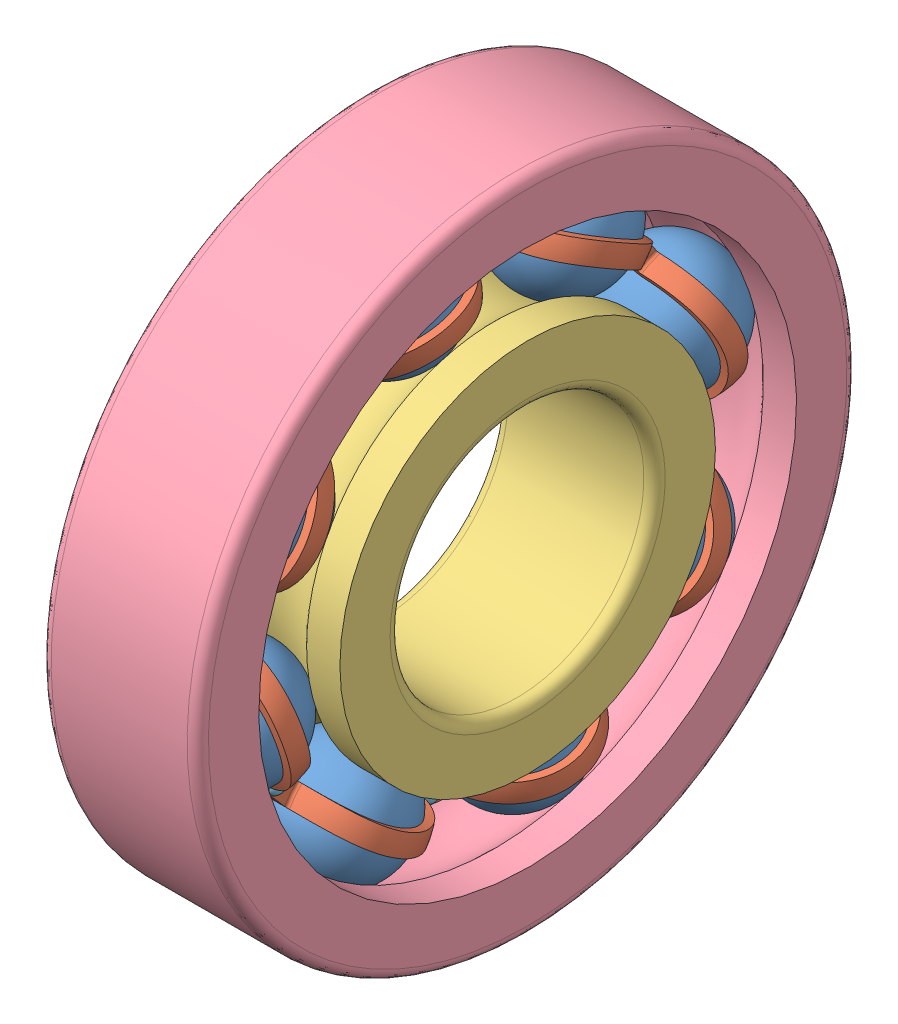
SolidWorks assembly ball_bearing, configuration Default. Lengths in mm.
Overall size (3.72 17.7 17.7).
20 component instances, 5 part files, 9 mates.
Components (placement in the parent):
- ball_bearing_ball-1: ball_bearing_ball [Default] at (25.5877 88.4804 104.5393) x (1 0 0) z (0 0.961807 -0.273728) size (2.88 2.88 2.88)
- ball_bearing_cage-1: ball_bearing_cage [Default] at (27.3885 93.2092 101.9319) x (0 0.96064 0.277796) z (-1 0 0) size (11.28 11.28 1.64)
- ball_bearing_inner_ring-1: ball_bearing_inner_ring [Default] at (25.5877 93.2092 101.9319) size (3.72 8.88 8.88)
- ball_bearing_outer_ring-1: ball_bearing_outer_ring [Default] at (25.5877 93.2092 101.9319) x (1 0 0) z (0 -0.144957 0.989438) size (3.72 15.6 15.6)
- ball_bearing_rivet-1: ball_bearing_rivet [Standard] at (25.4077 87.8425 102.5312) x (0 -0.277796 0.96064) z (0 0.96064 0.277796) size (0.44 0.62 0.44)
- ball_bearing_cage-2: ball_bearing_cage [Default] at (23.7868 93.2092 101.9319) x (0 -0.277796 0.96064) z (1 0 0) size (11.28 11.28 1.64)
- ball_bearing_rivet-9: ball_bearing_rivet [Standard] at (25.4077 89.8381 106.1505) x (0 0.482844 0.875707) z (0 0.875707 -0.482844) size (0.44 0.62 0.44)
- ball_bearing_rivet-10: ball_bearing_rivet [Standard] at (25.4077 93.8084 107.2986) x (0 0.96064 0.277796) z (0 0.277796 -0.96064) size (0.44 0.62 0.44)
- ball_bearing_rivet-11: ball_bearing_rivet [Standard] at (25.4077 97.4277 105.303) x (0 0.875707 -0.482844) z (0 -0.482844 -0.875707) size (0.44 0.62 0.44)
- ball_bearing_rivet-12: ball_bearing_rivet [Standard] at (25.4077 98.5758 101.3327) x (0 0.277796 -0.96064) z (0 -0.96064 -0.277796) size (0.44 0.62 0.44)
- ball_bearing_rivet-13: ball_bearing_rivet [Standard] at (25.4077 96.5803 97.7134) x (0 -0.482844 -0.875707) z (0 -0.875707 0.482844) size (0.44 0.62 0.44)
- ball_bearing_rivet-14: ball_bearing_rivet [Standard] at (25.4077 92.6099 96.5653) x (0 -0.96064 -0.277796) z (0 -0.277796 0.96064) size (0.44 0.62 0.44)
- ball_bearing_rivet-15: ball_bearing_rivet [Standard] at (25.4077 88.9907 98.5609) x (0 -0.875707 0.482844) z (0 0.482844 0.875707) size (0.44 0.62 0.44)
- ball_bearing_ball-16: ball_bearing_ball [Default] at (25.5877 91.7091 107.1194) x (1 0 0) z (0 0.486545 -0.873655) size (2.88 2.88 2.88)
- ball_bearing_ball-17: ball_bearing_ball [Default] at (25.5877 95.8165 106.6608) x (1 0 0) z (0 -0.273728 -0.961807) size (2.88 2.88 2.88)
- ball_bearing_ball-18: ball_bearing_ball [Default] at (25.5877 98.3966 103.432) x (1 0 0) z (0 -0.873655 -0.486545) size (2.88 2.88 2.88)
- ball_bearing_ball-19: ball_bearing_ball [Default] at (25.5877 97.938 99.3246) x (1 0 0) z (0 -0.961807 0.273728) size (2.88 2.88 2.88)
- ball_bearing_ball-20: ball_bearing_ball [Default] at (25.5877 94.7093 96.7445) x (1 0 0) z (0 -0.486545 0.873655) size (2.88 2.88 2.88)
- ball_bearing_ball-21: ball_bearing_ball [Default] at (25.5877 90.6018 97.2031) x (1 0 0) z (0 0.273728 0.961807) size (2.88 2.88 2.88)
- ball_bearing_ball-22: ball_bearing_ball [Default] at (25.5877 88.0217 100.4318) x (1 0 0) z (0 0.873655 0.486545) size (2.88 2.88 2.88)
Mates (geometry in assembly coordinates):
- Coincident1: coincident aligned: plane of ball_bearing_inner_ring-1 through (23.7277 96.4612 101.9319) normal (-1 0 0); plane of ball_bearing_outer_ring-1 through (23.7277 100.9268 103.0626) normal (-1 0 0)
- Concentric1: concentric aligned: cylinder of ball_bearing_inner_ring-1 through (22.6508 93.2092 101.9319) axis (-1 0 0) radius 3; cylinder of ball_bearing_outer_ring-1 through (24.0506 93.2092 101.9319) axis (-1 0 0) radius 7.8
- Concentric2: concentric anti-aligned: cylinder of ball_bearing_cage-1 through (25.5877 93.2092 101.9319) axis (1 0 0) radius 5.64; cylinder of ball_bearing_inner_ring-1 through (22.6508 93.2092 101.9319) axis (-1 0 0) radius 3
- Concentric3: concentric: sphere of ball_bearing_ball-1; sphere of ball_bearing_cage-1
- Tangent2: tangent anti-aligned: sphere of ball_bearing_ball-1; torus of ball_bearing_inner_ring-1
- Concentric4: concentric anti-aligned: cylinder of ball_bearing_cage-1 through (27.2077 87.8425 102.5312) axis (-1 0 0) radius 0.12; cylinder of ball_bearing_rivet-1 through (25.8966 87.8425 102.5312) axis (1 0 0) radius 0.12
- Coincident2: coincident anti-aligned: plane of ball_bearing_cage-1 through (25.7677 93.2092 101.9319) normal (1 0 0); plane of ball_bearing_rivet-1 through (25.7677 87.8759 102.4159) normal (-1 0 0)
- Concentric5: concentric aligned: cylinder of ball_bearing_inner_ring-1 through (22.6508 93.2092 101.9319) axis (-1 0 0) radius 3; cylinder of ball_bearing_cage-2 through (25.5877 93.2092 101.9319) axis (-1 0 0) radius 5.64
- Concentric6: concentric: sphere of ball_bearing_ball-1; sphere of ball_bearing_cage-2
